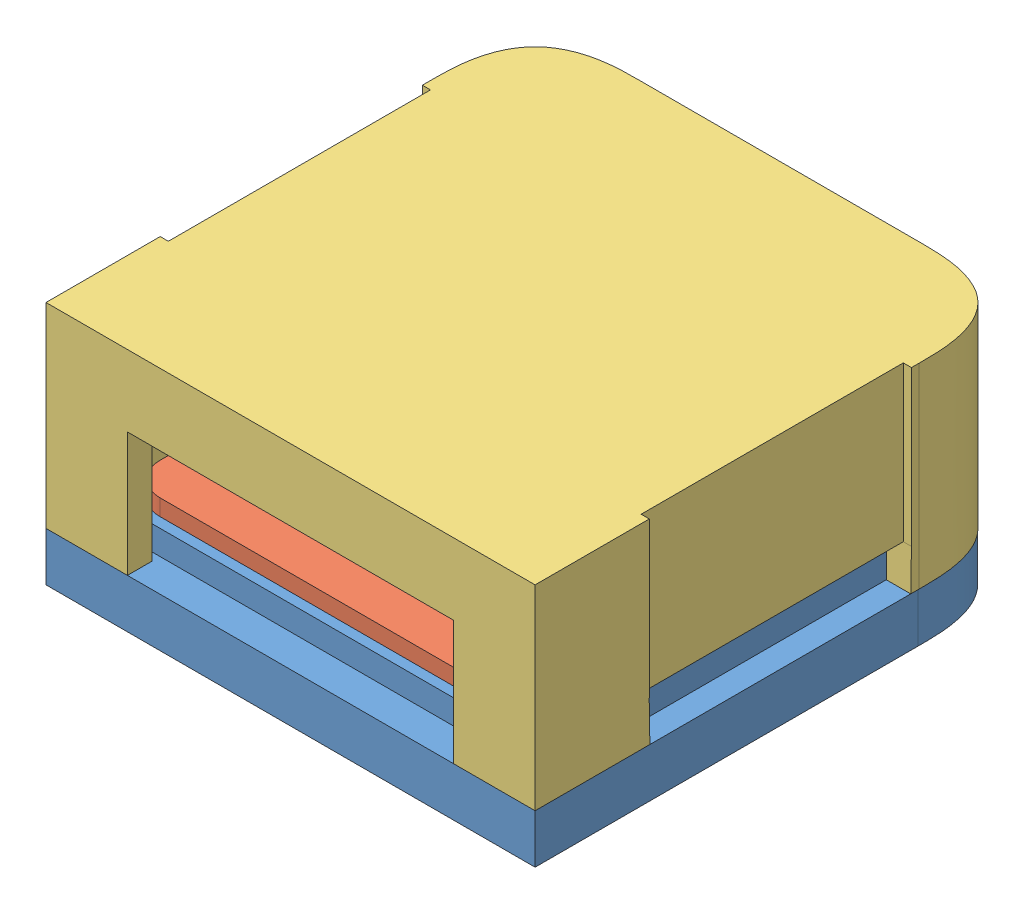
SolidWorks assembly ASSEMBLY_PICAM_CASE, configuration Default. Lengths in mm.
Overall size (30.1 15.89 30.05).
3 component instances, 3 part files, 4 mates.
Components (placement in the parent):
- PiCam Case_TOP-1: PiCam Case_TOP [Default] at (9.4852 15.0334 22.7679) size (30.1 4.6 30.05)
- PiCam V2.1-1: PiCam V2.1 [Default] at (9.4852 20.6534 23.2679) x (0 -1 0) z (1 0 0) size (6.48 24.01 25.01)
- PiCam Case_BOTTOM-1: PiCam Case_BOTTOM [Default] at (9.4852 30.0334 22.7679) x (-1 0 0) z (0 0 1) size (30.1 12.1 30.05)
Mates (geometry in assembly coordinates):
- Coincident2: coincident: axis of PiCam Case_TOP-1 through (-1.0148 19.5334 13.2679) axis (0 -1 0); axis of PiCam V2.1-1 through (-1.0148 21.2696 13.2679) axis (0 -1 0)
- Coincident3: coincident: axis of PiCam Case_TOP-1 through (-1.0148 19.5334 25.7679) axis (0 -1 0); axis of PiCam V2.1-1 through (-1.0148 21.2696 25.7679) axis (0 -1 0)
- Coincident5: coincident: line of PiCam Case_TOP-1 through (17.9852 18.0334 7.7679) axis (-1 0 0); line of PiCam Case_BOTTOM-1 through (0.9352 18.0334 7.7679) axis (1 0 0)
- Coincident6: coincident: line of PiCam Case_TOP-1 through (24.4852 18.0334 37.7679) axis (0 0 -1); line of PiCam Case_BOTTOM-1 through (24.4852 18.0334 30.7279) axis (0 0 1)
